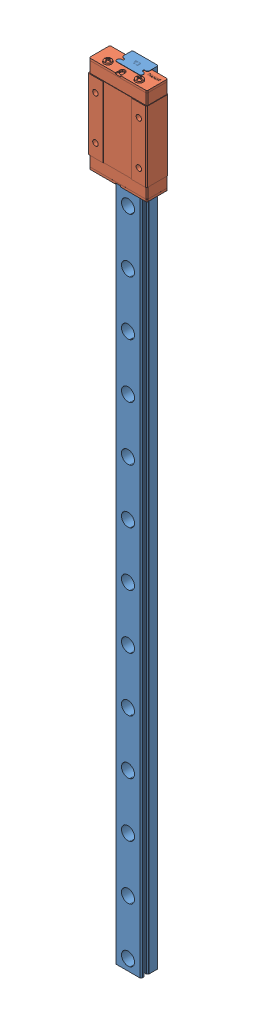
SolidWorks assembly Y Axis_Hiwin Rail MGNR12R-360-H-M-E5, configuration Default. Lengths in mm.
Overall size (48.36 360.04 28.96).
2 component instances, 2 part files, 3 mates.
Components (placement in the parent):
- Y-Rail-1: Y-Rail [Default] at (-28.8562 -186.9738 15.9648) size (12 360.04 8)
- Y-Slide-1: Y-Slide [Default] at (-28.8562 110.9932 15.9648) size (27 46.39 10)
Mates (geometry in assembly coordinates):
- Width1: width aligned: plane of Y-Rail-1 through (-22.8562 173.0262 16.4648) normal (1 0 0); plane of Y-Rail-1 through (-34.8562 173.0262 20.2866) normal (-1 0 0); plane of Y-Slide-1 through (-34.8562 172.8942 18.9648) normal (1 0 0); plane of Y-Slide-1 through (-22.8562 172.8942 20.2866) normal (-1 0 0)
- Concentric1: concentric aligned: cylinder of Y-Rail-1 through (-33.6205 173.0262 21.4208) axis (0 -1 0) radius 0.5; cylinder of Y-Slide-1 through (-33.6205 128.4942 21.4208) axis (0 -1 0) radius 0.5
- LimitDistance1: limit distance = 315.468 mm aligned: plane of Y-Slide-1 through (-42.1562 128.4942 18.9648) normal (0 -1 0); plane of Y-Rail-1 through (-34.8562 -186.9738 15.9648) normal (0 -1 0)
